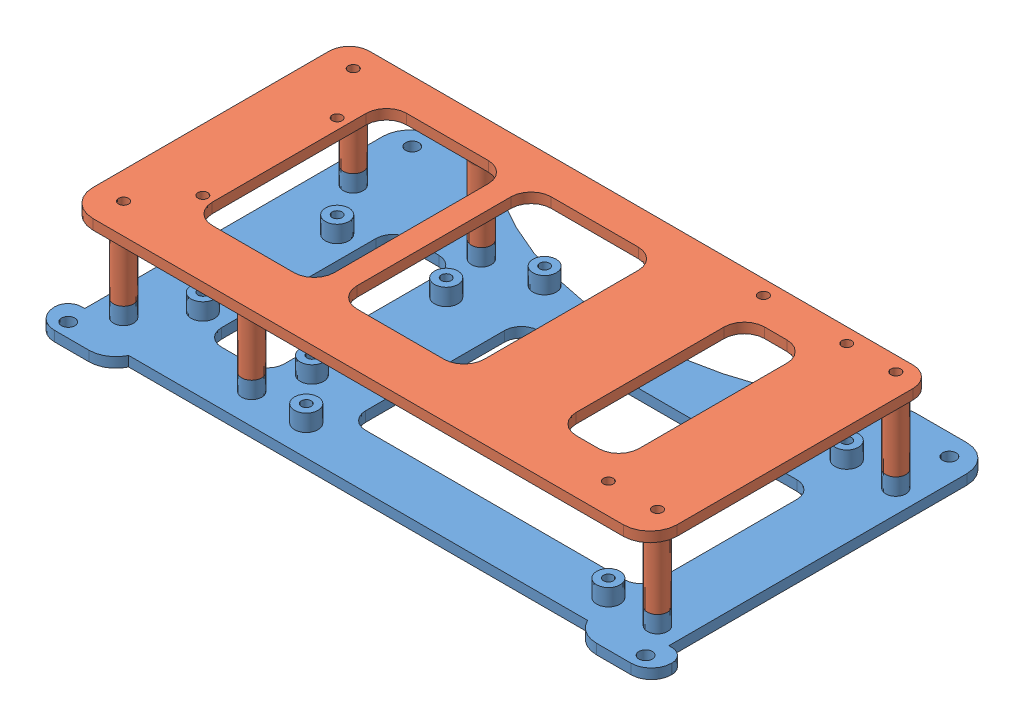
SolidWorks assembly 驱动模块支撑, configuration 默认. Lengths in mm.
Overall size (183.84 33 106.92).
2 component instances, 2 part files, 5 mates.
Components (placement in the parent):
- 底部支撑臂板-1: 底部支撑臂板 [默认] at (-12.4179 3.716 150.3829) size (183.84 8 106.92)
- 底部支撑臂上板-1: 底部支撑臂上板 [默认] at (-12.4179 36.716 150.3829) x (-1 0 0) z (0 0 1) size (174 25 84.37)
Mates (geometry in assembly coordinates):
- 平行1: parallel: plane of 底部支撑臂板-1 through (-12.4179 6.716 150.3829) normal (0 1 0); plane of 底部支撑臂上板-1 through (-12.4179 42.0554 150.3829) normal (0 1 0)
- 平行2: parallel: plane of 底部支撑臂板-1 through (55.9281 6.716 232.7356) normal (0 0 1); plane of 底部支撑臂上板-1 through (-99.4179 39.0554 232.7356) normal (0 0 1)
- 重合3: coincident: plane of 底部支撑臂板-1 through (-99.4179 6.716 227.1666) normal (-1 0 0); plane of 底部支撑臂上板-1 through (-99.4179 39.0554 170.3829) normal (-1 0 0)
- 重合4: coincident: plane of 底部支撑臂板-1 through (55.9281 6.716 232.7356) normal (0 0 1); plane of 底部支撑臂上板-1 through (-99.4179 39.0554 232.7356) normal (0 0 1)
- 重合5: coincident anti-aligned: plane of 底部支撑臂板-1 through (-91.3054 11.716 155.2856) normal (0 1 0); plane of 底部支撑臂上板-1 through (-91.3054 11.716 155.2856) normal (0 -1 0)
